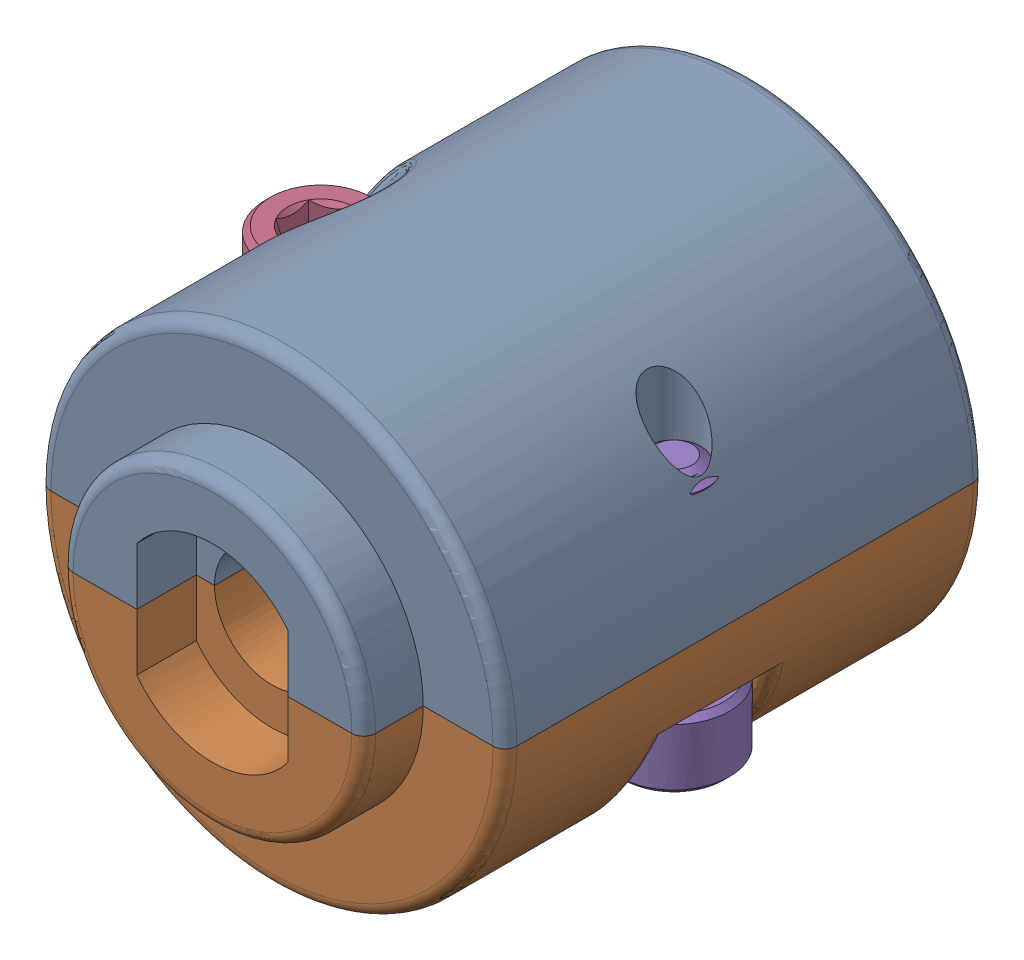
SolidWorks assembly 217-3195-200 Rev1, configuration Default. Lengths in mm.
Overall size (20.44 19.56 22.68).
5 component instances, 3 part files, 0 mates.
Components (placement in the parent):
- 217-3195-010 Rev1-1: 217-3195-010 Rev1 [Default] x (-1 0 0) z (0 0 1) size (19.61 11.78 22.68)
- 217-3195-010 Rev1-2: 217-3195-010 Rev1 [Default] at origin size (19.61 11.78 22.68)
- 217-2778-NCQ8A075-050M_1032_Nut_90545A111-1: 217-2778-NCQ8A075-050M_1032_Nut_90545A111 [Default] at (0 0 2.5527) x (-0.5 0.866025 0) z (0 0 1) size (9.53 11 3.39)
- 91251A107_91251A107-1: 91251A107_91251A107 [Default] at (-7.4168 -4.9375 -0.635) x (1 0 0) z (0 -1 0) size (4.65 4.65 10.79)
- 91251A107_91251A107-2: 91251A107_91251A107 [Default] at (7.4168 4.9375 -0.635) x (-0.837169 0 -0.546944) z (0 1 0) size (4.65 4.65 10.79)
